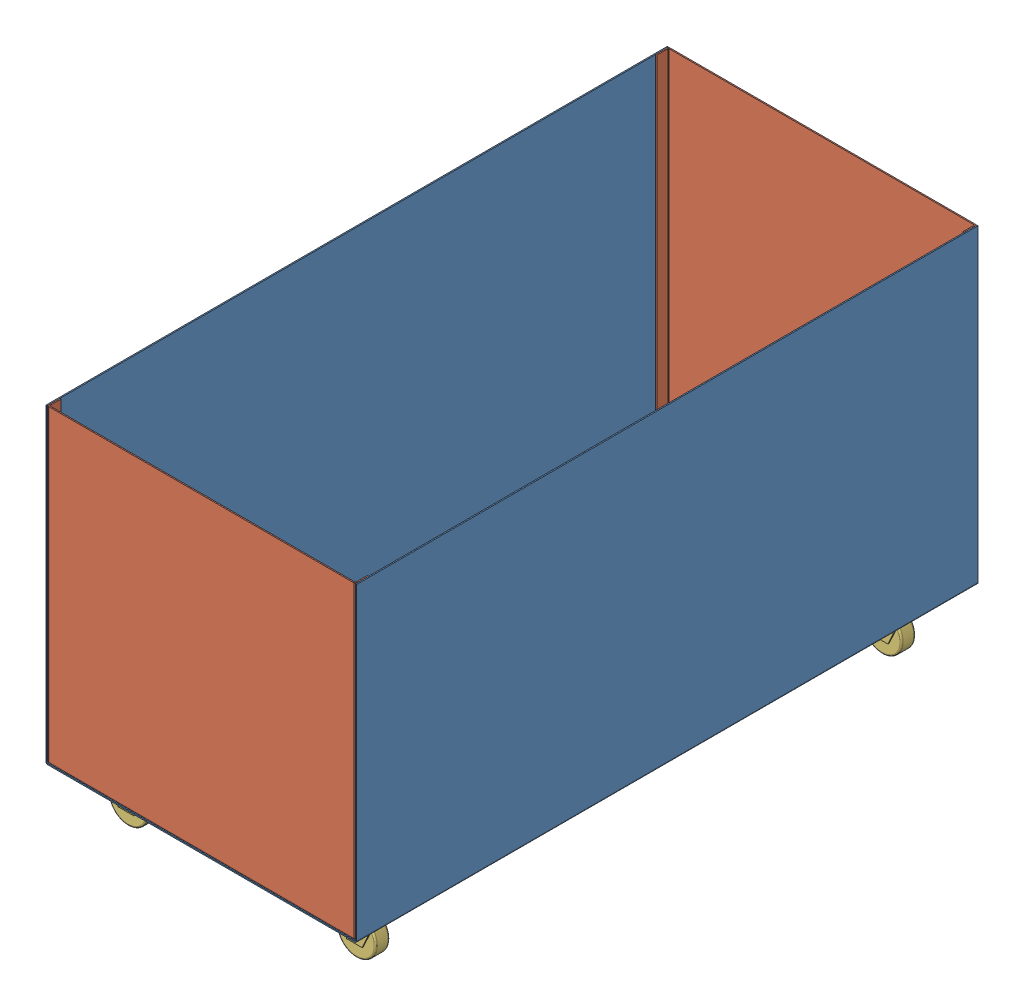
SolidWorks assembly KR.10.08, configuration Default. Lengths in mm.
Overall size (400 469.04 800).
7 component instances, 3 part files, 13 mates.
Components (placement in the parent):
- KR.12.07-1: KR.12.07 [Default] at origin size (400 400 800)
- KR.12.08-1: KR.12.08 [Default] at (0 201.8866 398.5) x (-1 0 0) z (0 0 -1) size (397.07 398.54 16.5)
- KR.12.08-2: KR.12.08 [Default] at (0 201.8866 -398.5) size (397.07 398.54 16.5)
- EP 02 ZKZ 50-1: EP 02 ZKZ 50 [Default] at (147 -51.5 327.75) size (66 69 23)
- EP 02 ZKZ 50-2: EP 02 ZKZ 50 [Default] at (-147 -51.5 327.75) size (66 69 23)
- EP 02 ZKZ 50-3: EP 02 ZKZ 50 [Default] at (-147 -51.5 -349.25) size (66 69 23)
- EP 02 ZKZ 50-4: EP 02 ZKZ 50 [Default] at (147 -51.5 -349.25) size (66 69 23)
Mates (geometry in assembly coordinates):
- Genişlik1: width aligned: plane of KR.12.08-1 through (-198.5366 201.8866 398.5) normal (-1 0 0); plane of KR.12.07-1 through (198.5366 201.8866 398.5) normal (1 0 0); plane of KR.12.08-1 through (198.5 400 400) normal (-1 0 0); plane of KR.12.07-1 through (-198.5 400 400) normal (1 0 0)
- Çakışık1: coincident anti-aligned: plane of KR.12.07-1 through (-200 1.5 400) normal (0 1 0); plane of KR.12.08-1 through (0 1.5 398.5) normal (0 -1 0)
- Genişlik2: width aligned: plane of KR.12.08-2 through (198.5366 201.8866 -398.5) normal (1 0 0); plane of KR.12.07-1 through (-198.5366 201.8866 -398.5) normal (-1 0 0); plane of KR.12.08-2 through (-198.5 400 400) normal (1 0 0); plane of KR.12.07-1 through (198.5 400 400) normal (-1 0 0)
- Çakışık2: coincident anti-aligned: plane of KR.12.07-1 through (-200 1.5 400) normal (0 1 0); plane of KR.12.08-2 through (0 1.5 -398.5) normal (0 -1 0)
- Çakışık3: coincident aligned: plane of KR.12.07-1 through (-197.7634 2.2366 -400) normal (0 0 -1); plane of KR.12.08-2 through (0 201.8866 -400) normal (0 0 -1)
- Çakışık4: coincident aligned: plane of KR.12.07-1 through (-197.7634 1.5 400) normal (0 0 1); plane of KR.12.08-1 through (0 201.8866 400) normal (0 0 1)
- Çakışık5: coincident anti-aligned: plane of KR.12.07-1 through (-200 0 400) normal (0 -1 0); plane of EP 02 ZKZ 50-2 through (-114 0 327) normal (0 1 0)
- Uzaklık1: distance = 50 mm aligned: plane of EP 02 ZKZ 50-2 through (-114 -1.5 350) normal (0 0 1); plane of KR.12.08-1 through (0 201.8866 400) normal (0 0 1)
- Uzaklık2: distance = 20 mm aligned: plane of EP 02 ZKZ 50-2 through (-180 0 350) normal (-1 0 0); plane of KR.12.07-1 through (-200 400 400) normal (-1 0 0)
- Çakışık6: coincident anti-aligned: plane of KR.12.07-1 through (-200 0 400) normal (0 -1 0); plane of EP 02 ZKZ 50-1 through (180 0 327) normal (0 1 0)
- Uzaklık3: distance = 50 mm aligned: plane of EP 02 ZKZ 50-1 through (180 -1.5 350) normal (0 0 1); plane of KR.12.08-1 through (0 201.8866 400) normal (0 0 1)
- Uzaklık4: distance = 20 mm aligned: plane of EP 02 ZKZ 50-1 through (180 0 350) normal (1 0 0); plane of KR.12.07-1 through (200 400 400) normal (1 0 0)
- Çakışık7: coordinate: point of KR.12.07-1
